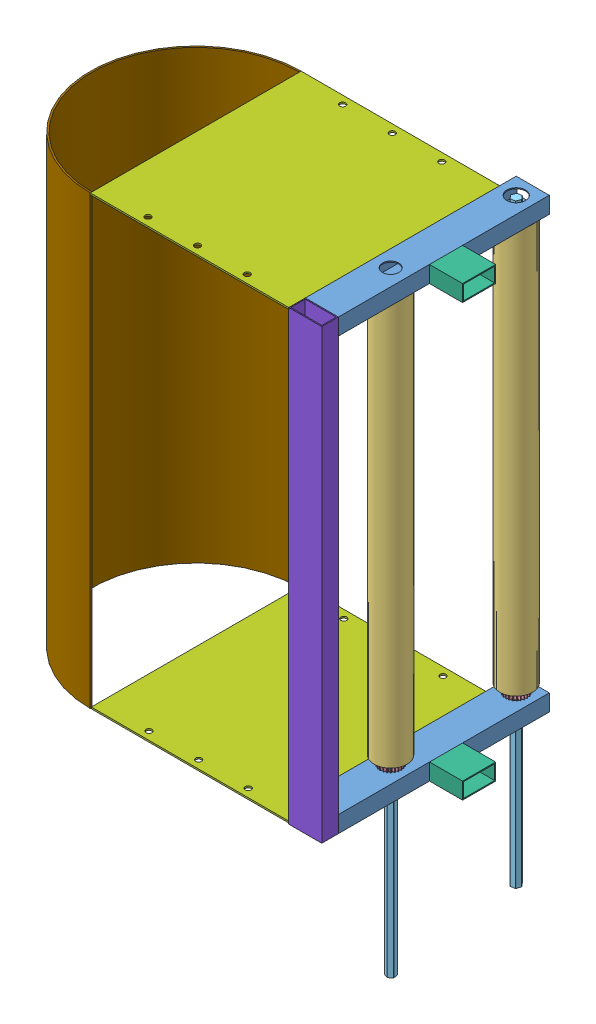
SolidWorks assembly power_cell_intake_assembly, configuration Default. Lengths in mm.
Overall size (568.32 939.8 355.88).
16 component instances, 9 part files, 28 mates.
Components (placement in the parent):
- intake_arm_front_right-1: intake_arm_front_right [Default] at (81.3332 173.9347 99.4996) size (50.8 25.4 323.85)
- intake_arm_front_right-2: intake_arm_front_right [Default] at (81.3441 -487.8358 99.4918) x (1 0 0.000428) z (-0.000428 0 1) size (50.8 25.4 323.85)
- PVC Spin Intake-1: PVC Spin Intake [Default] at (77.3045 -469.3654 82.8179) x (-0.638536 0 -0.769592) z (0 1 0) size (25.32 25.32 622.3)
- Foam Roller Intake-1: Foam Roller Intake [Default] at (99.5233 153.3037 124.8996) x (0.312683 0 0.949858) z (0 -1 0) size (50.65 50.65 622.3)
- VEX-217-2704-1: VEX-217-2704 [Default] at (99.8081 -475.69 125.1824) x (0.169371 0 0.985552) z (0 -1 0) size (33.29 33.29 12.65)
- VEX-217-2753-1: VEX-217-2753 [Default] at (99.7648 -280.02 125.1899) x (0.985552 0 -0.169371) z (0 1 0) size (14.51 12.7 914.4)
- Foam Roller Intake-2: Foam Roller Intake [Default] at (99.4407 153.928 317.6856) x (-0.64289 0 0.765958) z (0 -1 0) size (50.65 50.65 622.3)
- VEX-217-2753-2: VEX-217-2753 [Default] at (99.817 -303.2082 317.468) x (0.934773 0 0.355246) z (0 1 0) size (14.51 12.7 914.4)
- PVC Spin Intake-2: PVC Spin Intake [Default] at (139.5578 -468.3082 343.4333) x (0.934348 0 0.356363) z (0 1 0) size (25.32 25.32 622.3)
- VEX-217-2704-2: VEX-217-2704 [Default] at (99.9257 -474.6328 318.3785) x (0.355246 0 -0.934773) z (0 -1 0) size (33.29 33.29 12.65)
- arm_hardstop-1: arm_hardstop [Default] at (175.7233 167.7315 259.2971) x (0 0 1) z (0 -1 0) size (50.8 50.8 25.4)
- arm_hardstop-2: arm_hardstop [Default] at (175.6668 -496.1185 256.7907) x (0.000428 0 -1) z (0 1 0) size (50.8 50.8 25.4)
- intake_thicc_polycarbonate_wall-2: intake_thicc_polycarbonate_wall [Default] at (-382.372 -507.7788 141.6109) x (0.000428 0 -1) z (1 0 0.000428) size (323.85 2.48 304.8)
- intake_thicc_polycarbonate_wall-3: intake_thicc_polycarbonate_wall [Default] at (-382.3648 179.3918 430.2879) x (0 0 1) z (1 0 0) size (323.85 2.48 304.8)
- intake_arm_crossbar-1: intake_arm_crossbar [Default] at (87.1208 -507.7788 428.1984) x (1 0 0.000428) z (-0.000428 0 1) size (50.8 687.07 25.4)
- intake_top_cover-3: intake_top_cover [Default] at (-131.697 -506.4082 290.0714) x (0.00037 0 -1) z (1 0 0.00037) size (323.85 685.8 161.92)
Mates (geometry in assembly coordinates):
- Concentric8: concentric anti-aligned: circle of intake_arm_front_right-1; circle of Foam Roller Intake-1
- Parallel1: parallel anti-aligned: cylinder of PVC Spin Intake-1 through (99.5233 152.9346 124.8996) axis (0 -1 0) radius 12.659; cylinder of Foam Roller Intake-1 through (99.5233 -468.9963 124.8996) axis (0 1 0) radius 12.8268
- Coincident13: coincident anti-aligned: plane of PVC Spin Intake-1 through (95.0761 152.9346 119.5526) normal (0.938199 0 0.346097); plane of VEX-217-2753-1 through (95.0761 177.18 119.5526) normal (-0.938199 0 -0.346097)
- Coincident14: coincident anti-aligned: plane of PVC Spin Intake-1 through (101.9303 152.9346 118.3747) normal (0.169371 0 0.985552); plane of VEX-217-2753-1 through (102.3025 177.18 118.3107) normal (-0.169371 0 -0.985552)
- Concentric10: concentric anti-aligned: cylinder of PVC Spin Intake-1 through (99.5233 152.9346 124.8996) axis (0 -1 0) radius 12.659; cylinder of Foam Roller Intake-1 through (99.5233 -468.9963 124.8996) axis (0 1 0) radius 12.8268
- Coincident17: coincident anti-aligned: plane of VEX-217-2704-1 through (92.5384 -482.0146 126.4318) normal (0.768828 0 -0.639456); plane of VEX-217-2753-1 through (92.5384 177.18 126.4318) normal (-0.768828 0 0.639456)
- Coincident18: coincident anti-aligned: plane of VEX-217-2704-1 through (95.0913 -482.0146 119.5113) normal (0.938199 0 0.346097); plane of VEX-217-2753-1 through (95.0761 177.18 119.5526) normal (-0.938199 0 -0.346097)
- Coincident19: coincident anti-aligned: plane of PVC Spin Intake-1 through (99.5233 -469.3654 124.8996) normal (0 -1 0); plane of VEX-217-2704-1 through (99.8081 -469.3654 125.1824) normal (0 1 0)
- Concentric11: concentric anti-aligned: circle of intake_arm_front_right-2; circle of Foam Roller Intake-1
- Concentric16: concentric anti-aligned: circle of intake_arm_front_right-2; circle of Foam Roller Intake-2
- Tangent1: tangent: circle of intake_arm_front_right-1; circle of PVC Spin Intake-2
- Coincident20: coincident aligned: line of VEX-217-2753-2 through (94.4083 153.9918 322.2056) axis (0.934773 0 0.355246); line of PVC Spin Intake-2 through (94.1341 153.9918 322.1014) axis (0.934773 0 0.355246)
- Coincident21: coincident aligned: line of VEX-217-2753-2 through (93.0097 153.9918 315.1527) axis (0.159735 0 0.98716); line of PVC Spin Intake-2 through (93.0232 153.9918 315.236) axis (0.159735 0 0.98716)
- Coincident31: coincident anti-aligned: plane of VEX-217-2753-2 through (106.671 153.9918 320.0728) normal (0.98716 0 -0.159735); plane of VEX-217-2704-2 through (106.8209 -480.9574 320.9989) normal (-0.98716 0 0.159735)
- Coincident32: coincident anti-aligned: plane of PVC Spin Intake-2 through (99.5243 -468.3082 317.7066) normal (0 -1 0); plane of VEX-217-2704-2 through (99.9257 -468.3082 318.3785) normal (0 1 0)
- Coincident34: coincident: line of intake_arm_front_right-1 through (124.9233 179.3918 423.3496) axis (0 0 -1); line of arm_hardstop-1 through (124.9233 179.3918 283.5088) axis (0 0 -1)
- Coincident35: coincident anti-aligned: line of intake_arm_front_right-1 through (124.9233 153.9918 423.3496) axis (0 0 -1); line of arm_hardstop-1 through (124.9233 153.9918 232.7088) axis (0 0 1)
- Coincident36: coincident: line of intake_arm_front_right-2 through (124.7954 -507.7788 423.3604) axis (0.000428 0 -1); line of arm_hardstop-2 through (124.8772 -507.7788 232.5572) axis (-0.000428 0 1)
- Coincident37: coincident aligned: line of intake_arm_front_right-2 through (124.7954 -482.3788 423.3604) axis (0.000428 0 -1); line of arm_hardstop-2 through (124.8554 -482.3788 283.3572) axis (0.000428 0 -1)
- Coincident40: coincident: line of intake_arm_front_right-2 through (73.9954 -507.7788 423.3387) axis (1 0 0.000428); line of intake_arm_crossbar-1 through (124.7954 -507.7788 423.3604) axis (-1 0 -0.000428)
- Coincident42: coincident anti-aligned: line of intake_arm_front_right-2 through (124.7954 -507.7788 423.3604) axis (0 1 0); line of intake_arm_crossbar-1 through (124.7954 179.2912 423.3604) axis (0 -1 0)
- Symmetric1: symmetric aligned: line of intake_arm_front_right-2 through (73.9954 -507.7788 423.3387) axis (0.000428 0 -1); line of intake_thicc_polycarbonate_wall-2 through (73.9852 -507.7788 447.14) axis (0.000428 0 -1); plane of intake_thicc_polycarbonate_wall-2 through (-382.372 -507.7788 141.6109) normal (0 -1 0)
- Perpendicular8: perpendicular: plane of intake_arm_front_right-2 through (73.9954 -482.3788 423.3387) normal (-1 0 -0.000428); plane of intake_thicc_polycarbonate_wall-2 through (-382.372 -505.3023 141.6109) normal (0 1 0)
- Symmetric2: symmetric: line of intake_arm_front_right-1 through (74.1233 179.3918 423.3496) axis (0 0 -1); line of intake_thicc_polycarbonate_wall-3 through (74.1233 179.3918 124.9544) axis (0 0 1); plane of intake_thicc_polycarbonate_wall-3 through (-382.3648 179.3918 430.2879) normal (0 1 0)
- Perpendicular9: perpendicular: plane of intake_arm_front_right-1 through (74.1233 179.3918 423.3496) normal (-1 0 0); plane of intake_thicc_polycarbonate_wall-3 through (-382.3648 176.9153 430.2879) normal (0 -1 0)
- Perpendicular29: perpendicular: line of intake_thicc_polycarbonate_wall-3 through (-230.6767 179.3918 448.8044) axis (0 0 -1); line of intake_top_cover-3 through (-230.6767 179.3918 448.8044) axis (0 -1 0)
- Perpendicular30: perpendicular: line of intake_thicc_polycarbonate_wall-2 through (-230.676 -507.7788 123.1594) axis (-0.000428 0 1); line of intake_top_cover-3 through (-230.6767 179.3918 448.8044) axis (0 -1 0)
- Coincident86: coincident: point of intake_thicc_polycarbonate_wall-3; point of intake_top_cover-3
